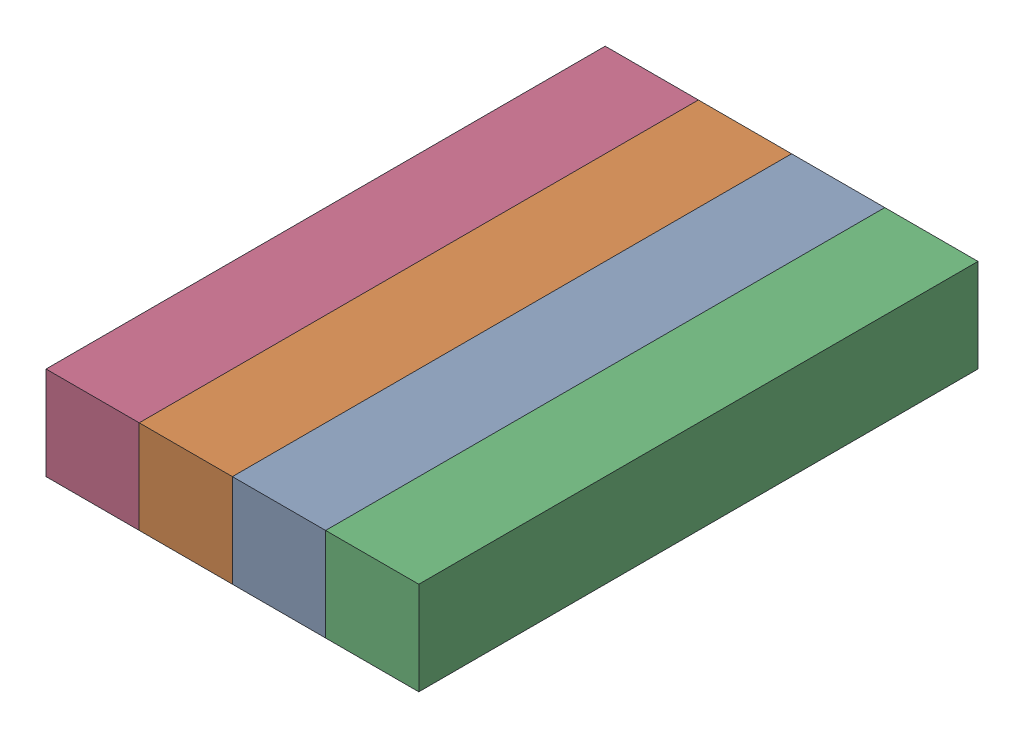
SolidWorks assembly Top, configuration Default. Lengths in mm.
Overall size (200 50 300).
4 component instances, 1 part files, 9 mates.
Components (placement in the parent):
- Upper-part-1: Upper-part [Default] at origin size (50 50 300)
- Upper-part-2: Upper-part [Default] at (-50 0 0) size (50 50 300)
- Upper-part-3: Upper-part [Default] at (50 0 0) size (50 50 300)
- Upper-part-4: Upper-part [Default] at (-100 0 0) size (50 50 300)
Mates (geometry in assembly coordinates):
- Coincident1: coincident anti-aligned: plane of Upper-part-2 through (-75 22.0879 300) normal (-1 0 0); plane of Upper-part-4 through (-75 22.0879 300) normal (1 0 0)
- Coincident2: coincident aligned: plane of Upper-part-2 through (-25 72.0879 300) normal (0 1 0); plane of Upper-part-4 through (-75 72.0879 300) normal (0 1 0)
- Coincident3: coincident aligned: plane of Upper-part-2 through (-50 47.0879 300) normal (0 0 1); plane of Upper-part-4 through (-100 47.0879 300) normal (0 0 1)
- Coincident4: coincident aligned: plane of Upper-part-1 through (0 0 300) normal (0 0 1); plane of Upper-part-2 through (-50 47.0879 300) normal (0 0 1)
- Coincident5: coincident: plane of Upper-part-1 through (0 0 300) normal (0 0 1); plane of Upper-part-3 through (50 -44.21 300) normal (0 0 1)
- Coincident7: coincident anti-aligned: plane of Upper-part-1 through (-25 -25 300) normal (-1 0 0); plane of Upper-part-2 through (-25 -25 300) normal (1 0 0)
- Coincident8: coincident: plane of Upper-part-1 through (25 -25 300) normal (1 0 0); plane of Upper-part-3 through (25 -25 300) normal (-1 0 0)
- Coincident9: coincident aligned: plane of Upper-part-1 through (25 25 300) normal (0 1 0); plane of Upper-part-2 through (-25 25 300) normal (0 1 0)
- Coincident10: coincident aligned: plane of Upper-part-1 through (25 25 300) normal (0 1 0); plane of Upper-part-3 through (75 25 300) normal (0 1 0)
